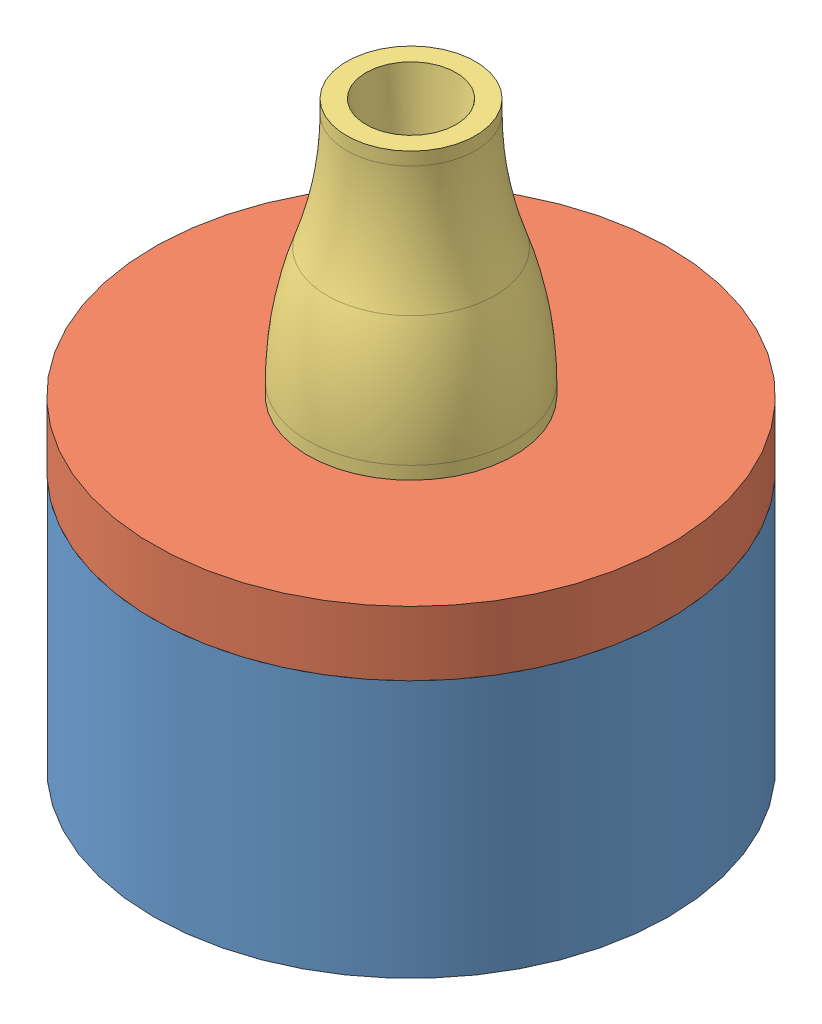
SolidWorks assembly round_assy, configuration Default. Lengths in mm.
Overall size (40.41 45 40.41).
3 component instances, 3 part files, 4 mates.
Components (placement in the parent):
- round_base-1: round_base [Default] at origin size (40 20 40)
- round_top-1: round_top [Default] at (0 15 0) x (0.999946 0 -0.010346) z (0.010346 0 0.999946) size (40 10 40)
- round_blow_hole-1: round_blow_hole [Default] at (0 25 0) x (0.99539 0 0.095906) z (-0.095906 0 0.99539) size (16 22 16)
Mates (geometry in assembly coordinates):
- Concentric1: concentric anti-aligned: cylinder of round_base-1 through (0 1.5 0) axis (0 1 0) radius 18; cylinder of round_top-1 through (0 15 0) axis (0 -1 0) radius 17.9
- Coincident1: coincident anti-aligned: plane of round_base-1 through (20 20 0) normal (0 1 0); plane of round_top-1 through (17.899 20 -0.1852) normal (0 -1 0)
- Concentric2: concentric: cylinder of round_top-1 through (0 15 0) axis (0 -1 0) radius 2.5; cylinder of round_blow_hole-1 through (0 43.0018 0) axis (0 -1 0) radius 2.4
- Coincident2: coincident anti-aligned: plane of round_top-1 through (19.9989 25 -0.2069) normal (0 1 0); plane of round_blow_hole-1 through (2.3889 25 0.2302) normal (0 -1 0)
